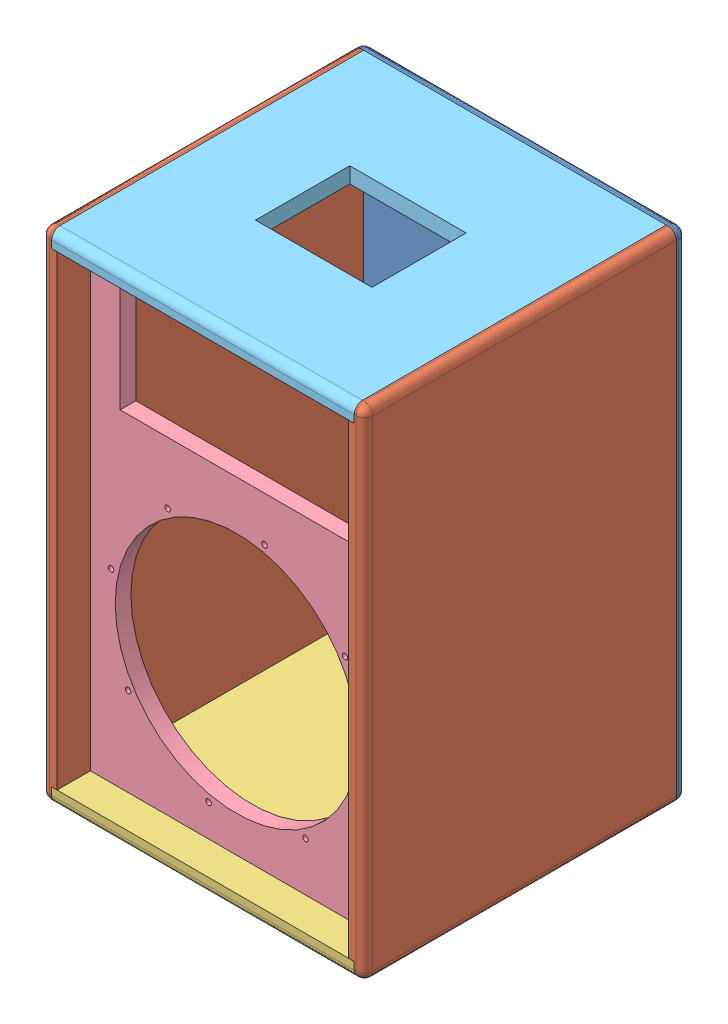
SolidWorks assembly SpeakerBox no electronics, configuration Default. Lengths in mm.
Overall size (370 570 369.15).
6 component instances, 5 part files, 15 mates.
Components (placement in the parent):
- back-1: back [Default] at (-203.5734 -231.6447 -35.6979) size (370 570 18)
- side-1: side [Default] at (-203.5734 -231.6447 333.4521) size (18 570 357.5)
- side-2: side [Default] at (166.4266 338.3553 333.4521) x (-1 0 0) z (0 0 1) size (18 570 357.5)
- top_bottom-2: top_bottom [Default] at (-191.9234 -231.6447 -24.0479) size (346.7 18 357.5)
- Baffle-1: Baffle [Default] at (-190.9234 -219.9947 277.3521) size (345.7 544.6 18)
- top-1: top [Default] at (154.7766 338.3553 -24.0479) x (-1 0 0) z (0 0 1) size (346.7 18 357.5)
Mates (geometry in assembly coordinates):
- Coincident1: coincident anti-aligned: plane of back-1 through (-203.5734 -231.6447 -24.0479) normal (0 0 1); plane of side-1 through (-185.5734 -231.6447 -24.0479) normal (0 0 -1)
- Coincident2: coincident aligned: plane of back-1 through (-203.5734 338.3553 -17.6979) normal (0 1 0); plane of side-1 through (-185.5734 338.3553 333.4521) normal (0 1 0)
- Coincident3: coincident aligned: plane of back-1 through (-203.5734 -231.6447 -17.6979) normal (-1 0 0); plane of side-1 through (-203.5734 -231.6447 333.4521) normal (-1 0 0)
- Coincident4: coincident aligned: plane of back-1 through (166.4266 -231.6447 -17.6979) normal (1 0 0); plane of side-2 through (166.4266 338.3553 333.4521) normal (1 0 0)
- Coincident5: coincident aligned: plane of back-1 through (-203.5734 338.3553 -17.6979) normal (0 1 0); plane of side-2 through (148.4266 338.3553 333.4521) normal (0 1 0)
- Coincident6: coincident anti-aligned: plane of back-1 through (-203.5734 -231.6447 -24.0479) normal (0 0 1); plane of side-2 through (148.4266 338.3553 -24.0479) normal (0 0 -1)
- Coincident10: coincident anti-aligned: plane of side-1 through (-191.9234 -213.6447 333.4521) normal (0 -1 0); plane of top_bottom-2 through (-191.9234 -213.6447 -24.0479) normal (0 1 0)
- Coincident11: coincident anti-aligned: plane of side-2 through (154.7766 338.3553 333.4521) normal (-1 0 0); plane of top_bottom-2 through (154.7766 -213.6447 -24.0479) normal (1 0 0)
- Coincident13: coincident anti-aligned: plane of back-1 through (-203.5734 -231.6447 -24.0479) normal (0 0 1); plane of top_bottom-2 through (-191.9234 -213.6447 -24.0479) normal (0 0 -1)
- Coincident14: coincident anti-aligned: plane of side-1 through (-191.9234 332.0053 277.3521) normal (0 0 1); plane of Baffle-1 through (-190.9234 -219.9947 277.3521) normal (0 0 -1)
- Coincident15: coincident anti-aligned: plane of top_bottom-2 through (-191.9234 -219.9947 -24.0479) normal (0 1 0); plane of Baffle-1 through (-190.9234 -219.9947 295.3521) normal (0 -1 0)
- Coincident16: coincident anti-aligned: plane of side-2 through (154.7766 338.3553 333.4521) normal (-1 0 0); plane of Baffle-1 through (154.7766 -219.9947 295.3521) normal (1 0 0)
- Coincident17: coincident anti-aligned: plane of side-1 through (-191.9234 -231.6447 333.4521) normal (1 0 0); plane of top-1 through (-191.9234 320.3553 -24.0479) normal (-1 0 0)
- Coincident18: coincident anti-aligned: plane of back-1 through (-203.5734 -231.6447 -24.0479) normal (0 0 1); plane of top-1 through (154.7766 320.3553 -24.0479) normal (0 0 -1)
- Coincident19: coincident aligned: plane of side-1 through (-185.5734 338.3553 333.4521) normal (0 1 0); plane of top-1 through (154.7766 338.3553 -24.0479) normal (0 1 0)
